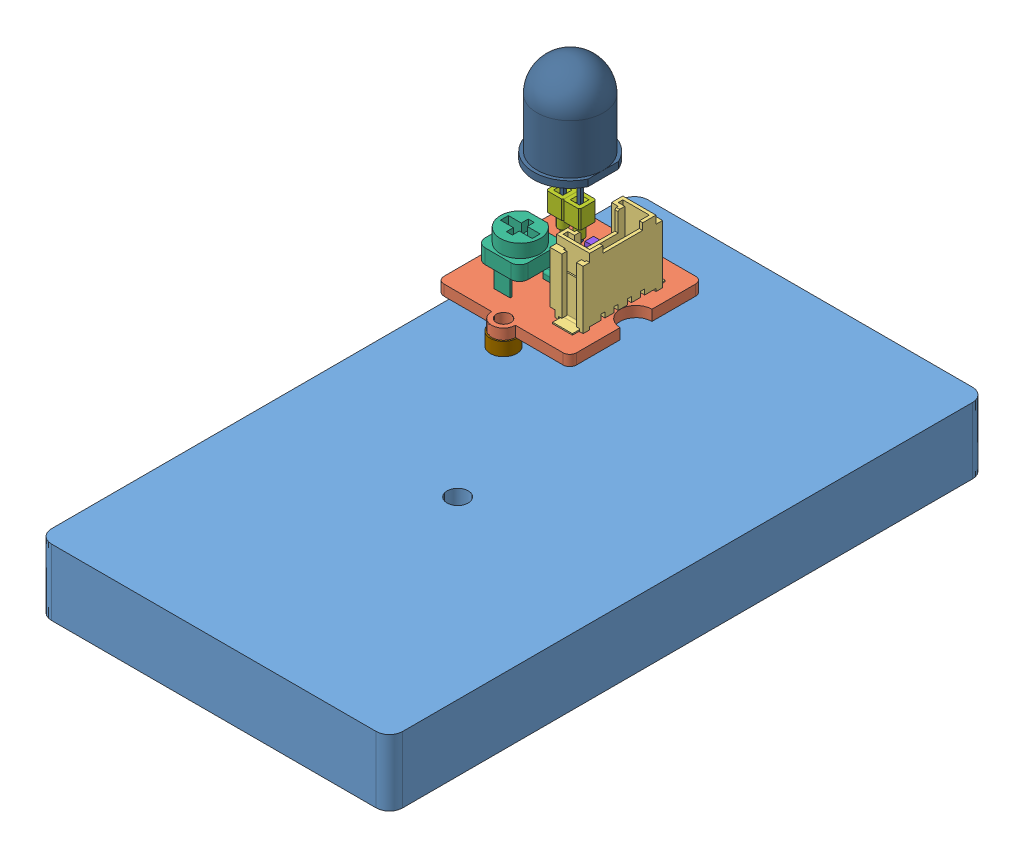
SolidWorks assembly chapeau_pilier_droit-complet, configuration Défaut. Lengths in mm.
Overall size (54.04 37.17 90).
15 component instances, 10 part files, 10 mates.
Components (placement in the parent):
- chapeau_pilier_droit-1: chapeau_pilier_droit [Défaut] at (-32.1329 -4.6037 135) size (53 10 90)
- Grove support LED-1: Grove support LED [Défaut] at (-29.3651 11.5804 65) size (20 13.2 23.6)
  - PCB grove 20x20-1: PCB grove 20x20 [Défaut] at (7.4555 -4.1841 0) size (20 1.6 23.6)
  - Connecteur Grove (droit CMS)-1: Connecteur Grove (droit CMS) [Défaut] at (10.4555 -2.5841 0) x (-1 0 0) z (0 1 0) size (6.5 14 10)
  - 603 resistor 102-2: 603 resistor 102 [Default] at (3.6365 -2.5841 -1.49) size (2.36 0.62 1.03)
  - 603 cap on pad-1: 603 cap on pad [Défaut] at (8.4655 -2.5841 -6.62) x (0 0 1) z (-1 0 0) size (2.76 0.91 1.12)
  - 603 resistor 102-3: 603 resistor 102 [Default] at (6.6365 -2.5841 -1.49) size (2.36 0.62 1.03)
  - 603 resistor 102-4: 603 resistor 102 [Default] at (6.6365 -2.5841 -2.99) size (2.36 0.62 1.03)
  - Pot - RES_VAR1-1: Pot - RES_VAR1 [Défaut] at (4.0824 2.7159 4.0972) size (6.5 10.5 7.06)
  - Contact F-1: Contact F [Défaut] at (0.621 0.0871 -5.7728) size (2.54 7.5 2.54)
  - ssot3-1: ssot3 [Default] at (6.0932 -2.5841 -5.7439) size (3 1.13 3.09)
  - Contact F-2: Contact F [Défaut] at (3.161 0.0871 -5.7728) size (2.54 7.5 2.54)
- entretoise-grove-1: entretoise-grove [Défaut] at (-21.9096 7.3963 55) x (1 0 0) z (0 -1 0) size (4 4 2)
- entretoise-grove-2: entretoise-grove [Défaut] at (-21.9096 7.3963 75) x (1 0 0) z (0 -1 0) size (4 4 2)
- chapeau_pilier_droit-led_jaune-10-1: chapeau_pilier_droit-led_jaune-10 [Default] at (-27.6741 19.0675 59.1772) x (1 0 0) z (0 1 0) size (10.5 11 23.5)
Mates (geometry in assembly coordinates):
- Coaxiale1: concentric anti-aligned: cylinder of Grove support LED-1/PCB grove 20x20-1 through (-21.9096 8.9963 55) axis (0 -1 0) radius 1.1; cylinder of entretoise-grove-1 through (-21.9096 5.3963 55) axis (0 1 0) radius 1
- Coaxiale2: concentric anti-aligned: cylinder of Grove support LED-1/PCB grove 20x20-1 through (-21.9096 8.9963 75) axis (0 -1 0) radius 1.1; cylinder of entretoise-grove-2 through (-21.9096 5.3963 75) axis (0 1 0) radius 1
- Coïncidente1: coincident anti-aligned: plane of Grove support LED-1/PCB grove 20x20-1 through (-21.9096 7.3963 65) normal (0 -1 0); plane of entretoise-grove-2 through (-21.9096 7.3963 75) normal (0 1 0)
- Coïncidente2: coincident anti-aligned: plane of Grove support LED-1/PCB grove 20x20-1 through (-21.9096 7.3963 65) normal (0 -1 0); plane of entretoise-grove-1 through (-21.9096 7.3963 55) normal (0 1 0)
- Coïncidente3: coincident anti-aligned: plane of chapeau_pilier_droit-1 through (18.8671 5.3963 47) normal (0 1 0); plane of entretoise-grove-1 through (-21.9096 5.3963 55) normal (0 -1 0)
- Coaxiale3: concentric aligned: cylinder of chapeau_pilier_droit-1 through (-21.9096 -4.6037 55) axis (0 1 0) radius 1; cylinder of entretoise-grove-1 through (-21.9096 5.3963 55) axis (0 1 0) radius 1
- Coaxiale4: concentric aligned: cylinder of chapeau_pilier_droit-1 through (-21.9096 -4.6037 75) axis (0 1 0) radius 1; cylinder of entretoise-grove-2 through (-21.9096 5.3963 75) axis (0 1 0) radius 1
- Coïncidente4: coincident anti-aligned: plane of Grove support LED-1/Contact F-2 through (-26.5041 14.4675 58.9272) normal (0 0 1); plane of LED 10mm Jaune-1 through (-27.6741 19.0675 58.9272) normal (0 0 -1)
- Coïncidente5: coincident anti-aligned: plane of Grove support LED-1/Contact F-2 through (-25.9041 14.4675 59.5272) normal (-1 0 0); plane of LED 10mm Jaune-1 through (-25.9041 19.0675 58.9272) normal (1 0 0)
- Distance1: distance = 5 mm: line of Grove support LED-1/Contact F-2 through (-25.9041 14.0675 58.9272) axis (-1 0 0); line of LED 10mm Jaune-1 through (-26.4041 9.0675 58.9272) axis (1 0 0)
